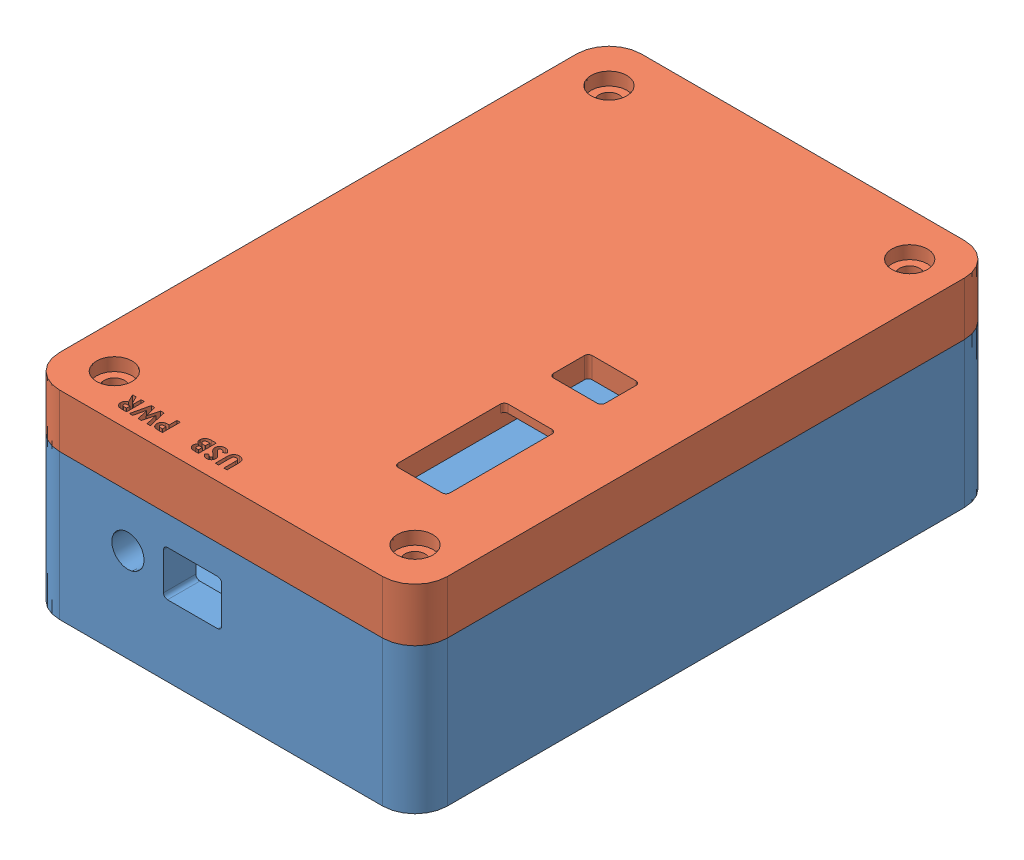
SolidWorks assembly MountingBox, configuration Default. Lengths in mm.
Overall size (76.2 39.05 114.3).
2 component instances, 2 part files, 3 mates.
Components (placement in the parent):
- MountingBox_Bottom-1: MountingBox_Bottom [Default] at (35.1703 43.122 81.7424) size (76.2 34.92 114.3)
- MountingBox_Top-1: MountingBox_Top [Default] at (35.1703 82.1745 81.7424) x (-1 0 0) z (0 0 1) size (76.2 10.48 114.3)
Mates (geometry in assembly coordinates):
- Coincident1: coincident anti-aligned: plane of MountingBox_Bottom-1 through (35.1703 78.047 81.7424) normal (0 1 0); plane of MountingBox_Top-1 through (35.1703 78.047 81.7424) normal (0 -1 0)
- Coincident2: coincident aligned: plane of MountingBox_Bottom-1 through (-2.9297 46.297 138.8924) normal (0 0 1); plane of MountingBox_Top-1 through (73.2703 78.047 138.8924) normal (0 0 1)
- Coincident3: coincident aligned: plane of MountingBox_Bottom-1 through (73.2703 46.297 138.8924) normal (1 0 0); plane of MountingBox_Top-1 through (73.2703 78.047 138.8924) normal (1 0 0)
